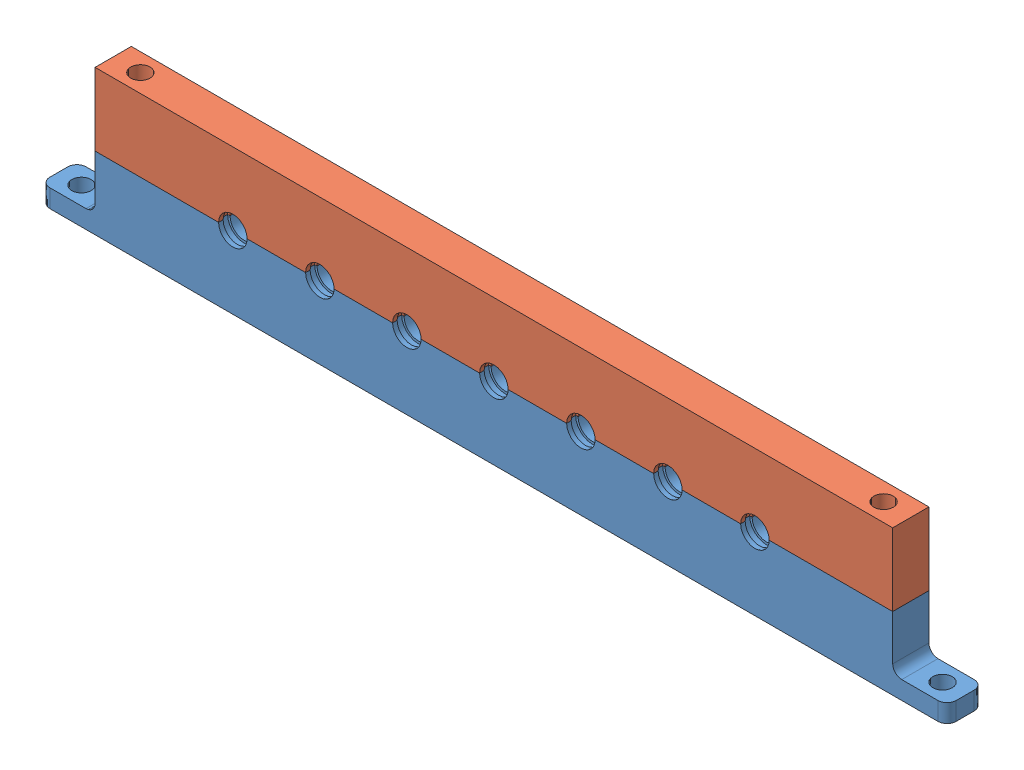
SolidWorks assembly led_assem, configuration Default. Lengths in mm.
Overall size (158.75 25.4 6.35).
3 component instances, 3 part files, 9 mates.
Components (placement in the parent):
- 5mm_led_mock-1: 5mm_led_mock [Default] at origin size (5.38 5.38 8.08) (hidden)
- bottom_led_stockade v2-1: bottom_led_stockade v2 [Default] at (0 -6.35 -5.5563) size (158.75 12.7 6.35)
- top_led_stockade v2-1: top_led_stockade v2 [Default] at (0 6.35 -5.5563) x (-1 0 0) z (0 0 1) size (139.7 12.7 6.35)
Mates (geometry in assembly coordinates):
- Coincident1: coincident aligned: plane of 5mm_led_mock-1 through (0 0 0) normal (1 0 0)
- Coincident2: coincident aligned: plane of 5mm_led_mock-1 through (0 0 0) normal (0 1 0)
- Coincident3: coincident aligned: plane of 5mm_led_mock-1 through (0 0 0) normal (0 0 1)
- Coincident4: coincident aligned: plane of bottom_led_stockade v2-1 through (0 -6.35 -5.5563) normal (1 0 0)
- Coincident5: coincident aligned: plane of 5mm_led_mock-1 through (0 0 0) normal (0 1 0); plane of bottom_led_stockade v2-1 through (69.85 0 0.7937) normal (0 1 0)
- Distance1: distance = 0.7937 mm aligned: plane of 5mm_led_mock-1 through (0 0 0) normal (0 0 1); plane of bottom_led_stockade v2-1 through (0 -6.35 0.7937) normal (0 0 1)
- Coincident6: coincident anti-aligned: plane of bottom_led_stockade v2-1 through (69.85 0 0.7937) normal (0 1 0); plane of top_led_stockade v2-1 through (-69.85 0 0.7937) normal (0 -1 0)
- Concentric1: concentric aligned: cylinder of bottom_led_stockade v2-1 through (-65.0875 0 -2.3813) axis (0 1 0) radius 1.25; cylinder of top_led_stockade v2-1 through (-65.0875 12.7 -2.3813) axis (0 1 0) radius 1.7
- Concentric2: concentric aligned: cylinder of bottom_led_stockade v2-1 through (65.0875 0 -2.3813) axis (0 1 0) radius 1.25; cylinder of top_led_stockade v2-1 through (65.0875 12.7 -2.3813) axis (0 1 0) radius 1.7
